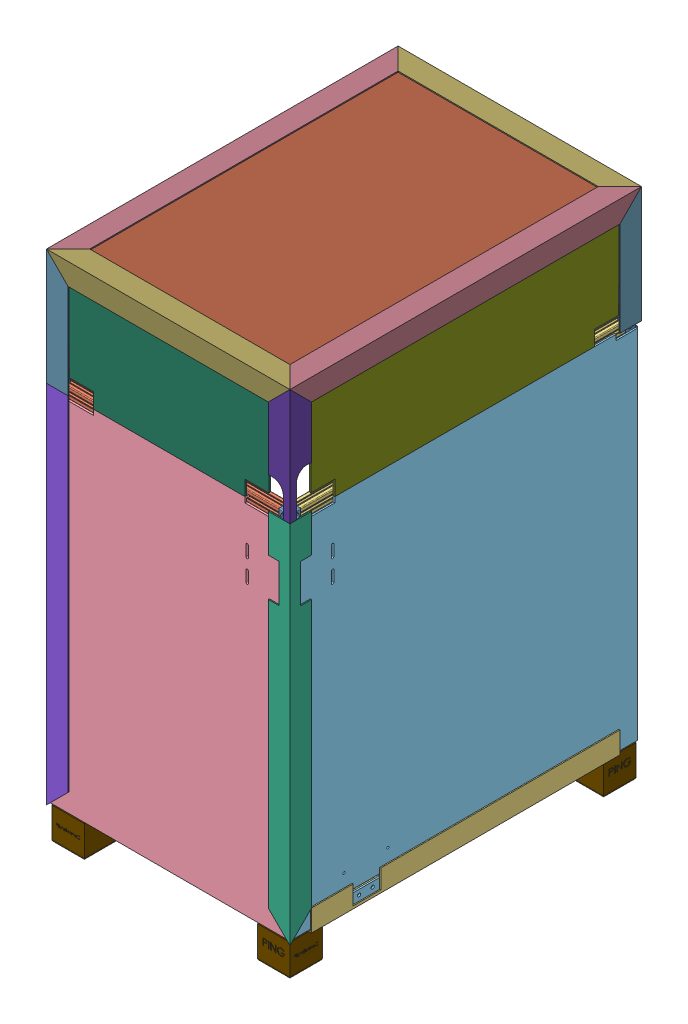
SolidWorks assembly carcasse, configuration Défaut. Lengths in mm.
Overall size (450 950 650).
53 component instances, 24 part files, 63 mates.
Components (placement in the parent):
- cadre-1: cadre [Défaut] at (-215.194 -19.8636 -400) size (440 20 640)
  - Blocks-1: Blocks [Défaut] at (-153.6103 82.5412 1245.1575) x (0 1 0) z (0 0 1) size (20 20 20)
  - Blocks-3: Blocks [Défaut] at (-153.6103 62.5412 625.1575) x (0 0 -1) z (0 1 0) size (20 20 20)
  - Blocks-4: Blocks [Défaut] at (246.3897 82.5412 645.1575) x (0 1 0) z (0 0 -1) size (20 20 20)
  - Blocks-5: Blocks [Défaut] at (246.3897 62.5412 1265.1575) x (0 0 1) z (0 1 0) size (20 20 20)
  - prof_20x20x400mm-1: prof_20x20x400mm [End Finishing_Non-Machined End Finish Options_Type_Single_] at (246.3897 72.5412 635.1575) x (0 0 1) z (-1 0 0) size (20 20 400)
  - prof_20x20x400mm-2: prof_20x20x400mm [End Finishing_Non-Machined End Finish Options_Type_Single_] at (246.3897 72.5412 1255.1575) x (0 0 1) z (-1 0 0) size (20 20 400)
  - prof_20x20x600mm-4: prof_20x20x600mm [End Finishing_Non-Machined End Finish Options_Type_Single_] at (256.3897 72.5412 645.1575) size (20 20 600)
  - prof_20x20x600mm-5: prof_20x20x600mm [End Finishing_Non-Machined End Finish Options_Type_Single_] at (-163.6103 72.5412 645.1575) size (20 20 600)
- prof_20x20x640mm-1: prof_20x20x640mm [End Finishing_Non-Machined End Finish Options_Type_Single_] at (41.1957 42.6776 235.1575) x (1 0 0) z (0 -1 0) size (20 20 640)
- prof_20x20x640mm-2: prof_20x20x640mm [End Finishing_Non-Machined End Finish Options_Type_Single_] at (41.1957 42.6776 855.1575) x (1 0 0) z (0 -1 0) size (20 20 640)
- prof_20x20x640mm-3: prof_20x20x640mm [End Finishing_Non-Machined End Finish Options_Type_Single_] at (-378.8043 42.6776 855.1575) x (1 0 0) z (0 -1 0) size (20 20 640)
- prof_20x20x640mm-4: prof_20x20x640mm [End Finishing_Non-Machined End Finish Options_Type_Single_] at (-378.8043 42.6776 235.1575) x (1 0 0) z (0 -1 0) size (20 20 640)
- cadre-2: cadre [Défaut] at (-122.4146 -534.7812 -400) x (-1 0 0) z (0 0 1) size (440 20 640)
  - Blocks-1: Blocks [Défaut] at (-153.6103 82.5412 1245.1575) x (0 1 0) z (0 0 1) size (20 20 20)
  - Blocks-3: Blocks [Défaut] at (-153.6103 62.5412 625.1575) x (0 0 -1) z (0 1 0) size (20 20 20)
  - Blocks-4: Blocks [Défaut] at (246.3897 82.5412 645.1575) x (0 1 0) z (0 0 -1) size (20 20 20)
  - Blocks-5: Blocks [Défaut] at (246.3897 62.5412 1265.1575) x (0 0 1) z (0 1 0) size (20 20 20)
  - prof_20x20x400mm-1: prof_20x20x400mm [End Finishing_Non-Machined End Finish Options_Type_Single_] at (246.3897 72.5412 635.1575) x (0 0 1) z (-1 0 0) size (20 20 400)
  - prof_20x20x400mm-2: prof_20x20x400mm [End Finishing_Non-Machined End Finish Options_Type_Single_] at (246.3897 72.5412 1255.1575) x (0 0 1) z (-1 0 0) size (20 20 400)
  - prof_20x20x600mm-4: prof_20x20x600mm [End Finishing_Non-Machined End Finish Options_Type_Single_] at (256.3897 72.5412 645.1575) size (20 20 600)
  - prof_20x20x600mm-5: prof_20x20x600mm [End Finishing_Non-Machined End Finish Options_Type_Single_] at (-163.6103 72.5412 645.1575) size (20 20 600)
- plaque_acrylique_680x670-2: plaque_acrylique_680x670 [Défaut] at (51.1957 -282.3224 525.1575) x (0 0 -1) z (1 0 0) size (640 670 3)
- plaque_acrylique_380x670_G-1: plaque_acrylique_380x670_G [Défaut] at (-138.8043 -282.3224 222.1575) size (440 670 3)
- plaque_acrylique_680x670_porte-1: plaque_acrylique_680x670_porte [Défaut] at (-391.8043 -282.3224 525.1575) x (0 0 -1) z (1 0 0) size (640 670 3)
- eclisse_40x40x670_bisote_x1-1: eclisse_40x40x670_bisote_x1 [Défaut] at (-373.8043 -622.3224 240.2711) size (40 675 40)
- eclisse_40x40x670_bisote_x1-2: eclisse_40x40x670_bisote_x1 [Défaut] at (-373.6907 -622.3224 850.1575) x (0 0 -1) z (1 0 0) size (40 675 40)
- eclisse_40x40x670_bisote_x1-4: eclisse_40x40x670_bisote_x1 [Défaut] at (36.0821 -622.3224 240.1575) x (0 0 1) z (-1 0 0) size (40 675 40) (hidden)
- couvercle-1: couvercle [Défaut] at (191.3923 156.5575 835.9918) size (450 215 650)
  - plaque_acrylique_680x210-2: plaque_acrylique_680x210 [Défaut] at (-583.1966 1.1201 -270.8343) x (0 0 -1) z (1 0 0) size (640 210 3)
  - plaque_acrylique_380x210-2: plaque_acrylique_380x210 [Défaut] at (-330.1966 1.1201 -613.8343) size (440 210 3)
  - plaque_acrylique_380x680-1: plaque_acrylique_380x680 [Défaut] at (-330.1966 106.1201 -270.8343) x (1 0 0) z (0 1 0) size (440 640 3)
  - eclisse_40x40x404_bisote_x2-1: eclisse_40x40x404_bisote_x2 [Défaut] at (-135.1966 91.0065 -595.8343) x (0 0 1) z (0 -1 0) size (40 450 40)
  - eclisse_40x40x704_bisote_x2-1: eclisse_40x40x704_bisote_x2 [Défaut] at (-155.3102 91.1201 -615.8343) x (0 -1 0) z (-1 0 0) size (40 650 40)
  - eclisse_40x40x404_bisote_x2-2: eclisse_40x40x404_bisote_x2 [Défaut] at (-585.1966 91.0065 14.1657) x (0 0 -1) z (0 -1 0) size (40 450 40)
  - eclisse_40x40x704_bisote_x2-2: eclisse_40x40x704_bisote_x2 [Défaut] at (-565.1966 91.0065 -615.8343) x (1 0 0) z (0 -1 0) size (40 650 40)
  - eclisse_40x40x222_bisote_x1-1: eclisse_40x40x222_bisote_x1 [Défaut] at (-565.083 111.1201 -595.8343) x (0 0 1) z (1 0 0) size (40 215 40)
  - eclisse_40x40x222_bisote_x1-2: eclisse_40x40x222_bisote_x1 [Défaut] at (-155.1966 111.1201 -595.7207) x (-1 0 0) z (0 0 1) size (40 215 40)
  - eclisse_40x40x222_bisote_x1-4: eclisse_40x40x222_bisote_x1 [Défaut] at (-565.1966 111.1201 14.052) x (1 0 0) z (0 0 -1) size (40 215 40)
  - plaque_acrylique_380x210_Moteur-1: plaque_acrylique_380x210_Moteur [Défaut] at (-330.1966 1.1201 29.1657) size (440 210 3)
  - plaque_acrylique_680x210_moteur-1: plaque_acrylique_680x210_moteur [Défaut] at (-140.1966 1.1201 -270.8343) x (0 0 -1) z (1 0 0) size (640 210 3)
  - eclisse_40x40x222_bisote_x1_Moteur-1: eclisse_40x40x222_bisote_x1_Moteur [Défaut] at (-155.3102 111.1201 14.1657) x (0 0 -1) z (-1 0 0) size (40 215 40)
- Pied-1: Pied [Défaut] at (-8.8043 -622.3224 285.1575) x (-1 0 0) z (0 -1 0) size (60 60 60)
- Pied-2: Pied [Défaut] at (-8.8043 -622.3224 805.1575) x (0 0 -1) z (0 -1 0) size (60 60 60)
- Pied-3: Pied [Défaut] at (-328.8043 -622.3224 805.1575) x (1 0 0) z (0 -1 0) size (60 60 60)
- Pied-4: Pied [Défaut] at (-328.8043 -622.3224 285.1575) x (0 0 1) z (0 -1 0) size (60 60 60)
- eclisse_bas_40x40x704-2: eclisse_bas_40x40x704 [Défaut] at (-373.8043 -602.2087 830.1575) x (1 0 0) z (0 1 0) size (40 570 40) (hidden)
- eclisse_bas_40x40x404-1: eclisse_bas_40x40x404 [Défaut] at (-353.8043 -602.2087 240.1575) x (0 0 1) z (0 1 0) size (40 370 40) (hidden)
- eclisse_bas_40x40x404-2: eclisse_bas_40x40x404 [Défaut] at (16.1957 -602.2087 850.1575) x (0 0 -1) z (0 1 0) size (40 370 40) (hidden)
- eclisse_bas_support_Z_40x40x704-1: eclisse_bas_support_Z_40x40x704 [Défaut] at (36.0821 -602.3224 830.1575) x (0 1 0) z (-1 0 0) size (40 570 40) (hidden)
- plaque_acrylique_380x670_D-2: plaque_acrylique_380x670_D [Défaut] at (-198.8043 -282.3224 848.1575) x (-1 0 0) z (0 0 -1) size (440 670 23) (hidden)
- plaque_acrylique_bas_380x680-1: plaque_acrylique_bas_380x680 [Défaut] at (-138.8043 -620.3224 565.1575) x (1 0 0) z (0 1 0) size (440 640 3)
- eclisse_40x40x670_bisote_x1-Moteur-1: eclisse_40x40x670_bisote_x1-Moteur [Défaut] at (36.1957 -622.3224 850.0438) x (-1 0 0) z (0 0 -1) size (40 675 40) (hidden)
Mates (geometry in assembly coordinates):
- Coïncidente66: coincident anti-aligned: plane of plaque_acrylique_680x670_porte-1 through (-391.8043 -282.3224 525.1575) normal (-1 0 0); plane of eclisse_40x40x670_bisote_x1-1 through (-391.8043 52.6776 222.1575) normal (1 0 0)
- Coïncidente67: coincident aligned: plane of plaque_acrylique_680x670_porte-1 through (-388.8043 52.6776 865.1575) normal (0 1 0); plane of eclisse_40x40x670_bisote_x1-1 through (-373.8043 52.6776 240.2711) normal (0 1 0)
- Coïncidente68: coincident anti-aligned: plane of plaque_acrylique_680x670-2 through (54.1957 -282.3224 525.1575) normal (1 0 0); plane of eclisse_40x40x670_bisote_x1-4 through (54.1957 52.6776 222.1575) normal (-1 0 0)
- Coïncidente72: coincident anti-aligned: plane of plaque_acrylique_680x670_porte-1 through (-391.8043 -282.3224 525.1575) normal (-1 0 0); plane of eclisse_40x40x670_bisote_x1-2 through (-391.8043 52.6776 868.1575) normal (1 0 0)
- Coïncidente100: coincident: plane of plaque_acrylique_680x670_porte-1 through (-388.8043 52.6776 865.1575) normal (0 1 0); line of eclisse_40x40x670_bisote_x1-2 through (-391.8043 52.6776 868.1575) axis (0 0 -1)
- Coïncidente132: coincident anti-aligned: plane of plaque_acrylique_680x670_porte-1 through (-391.8043 -282.3224 525.1575) normal (-1 0 0); plane of eclisse_bas_40x40x704-2 through (-391.8043 -620.3224 260.1575) normal (1 0 0)
- Coïncidente134: coincident anti-aligned: line of eclisse_40x40x670_bisote_x1-2 through (-393.8043 52.6776 830.1575) axis (0 -1 0); line of eclisse_bas_40x40x704-2 through (-393.8043 -622.3224 830.1575) axis (0 1 0)
- Coïncidente142: coincident anti-aligned: plane of plaque_acrylique_680x670-2 through (54.1957 -282.3224 525.1575) normal (1 0 0); plane of eclisse_bas_support_Z_40x40x704-1 through (54.1957 -620.3224 260.1575) normal (-1 0 0)
- Coïncidente156: coincident anti-aligned: plane of eclisse_bas_40x40x404-2 through (-353.8043 -620.3224 868.1575) normal (0 0 -1); plane of plaque_acrylique_380x670_D-2 through (-198.8043 -282.3224 868.1575) normal (0 0 1)
- Coïncidente157: coincident anti-aligned: plane of eclisse_40x40x670_bisote_x1-2 through (-391.8043 52.6776 868.1575) normal (0 0 -1); plane of plaque_acrylique_380x670_D-2 through (-198.8043 -282.3224 868.1575) normal (0 0 1)
- Coïncidente163: coincident anti-aligned: plane of cadre-1/Blocks-1 through (-388.8043 42.6776 865.1575) normal (0 -1 0); plane of prof_20x20x640mm-3 through (-387.3043 42.6776 863.6575) normal (0 1 0)
- Coïncidente164: coincident aligned: plane of cadre-1/Blocks-1 through (-388.8043 42.6776 865.1575) normal (-1 0 0); plane of prof_20x20x640mm-3 through (-388.8043 -597.3224 858.9075) normal (-1 0 0)
- Coïncidente165: coincident aligned: plane of cadre-1/Blocks-1 through (-368.8043 62.6776 865.1575) normal (0 0 1); plane of prof_20x20x640mm-3 through (-382.5543 -597.3224 865.1575) normal (0 0 1)
- Coïncidente166: coincident anti-aligned: plane of prof_20x20x640mm-3 through (-387.3043 -597.3224 863.6575) normal (0 -1 0); plane of cadre-2/Blocks-5 through (-368.8043 -597.3224 865.1575) normal (0 1 0)
- Coïncidente167: coincident aligned: plane of prof_20x20x640mm-3 through (-382.5543 -597.3224 865.1575) normal (0 0 1); plane of cadre-2/Blocks-5 through (-388.8043 -617.3224 865.1575) normal (0 0 1)
- Coïncidente168: coincident aligned: plane of prof_20x20x640mm-3 through (-388.8043 -597.3224 858.9075) normal (-1 0 0); plane of cadre-2/Blocks-5 through (-388.8043 -617.3224 845.1575) normal (-1 0 0)
- Coïncidente169: coincident anti-aligned: plane of prof_20x20x640mm-2 through (32.6957 -597.3224 863.6575) normal (0 -1 0); plane of cadre-2/Blocks-1 through (51.1957 -597.3224 865.1575) normal (0 1 0)
- Coïncidente170: coincident aligned: plane of prof_20x20x640mm-2 through (37.4457 -597.3224 865.1575) normal (0 0 1); plane of cadre-2/Blocks-1 through (31.1957 -617.3224 865.1575) normal (0 0 1)
- Coïncidente171: coincident aligned: plane of prof_20x20x640mm-2 through (51.1957 -597.3224 858.9075) normal (1 0 0); plane of cadre-2/Blocks-1 through (51.1957 -597.3224 865.1575) normal (1 0 0)
- Coïncidente172: coincident anti-aligned: plane of prof_20x20x640mm-1 through (32.6957 -597.3224 243.6575) normal (0 -1 0); plane of cadre-2/Blocks-3 through (31.1957 -597.3224 225.1575) normal (0 1 0)
- Coïncidente173: coincident aligned: plane of prof_20x20x640mm-1 through (51.1957 -597.3224 238.9075) normal (1 0 0); plane of cadre-2/Blocks-3 through (51.1957 -617.3224 245.1575) normal (1 0 0)
- Coïncidente174: coincident aligned: plane of prof_20x20x640mm-1 through (44.9457 -597.3224 225.1575) normal (0 0 -1); plane of cadre-2/Blocks-3 through (51.1957 -617.3224 225.1575) normal (0 0 -1)
- Coïncidente175: coincident aligned: plane of cadre-1/Blocks-3 through (-388.8043 62.6776 245.1575) normal (-1 0 0); plane of prof_20x20x640mm-4 through (-388.8043 -597.3224 231.4075) normal (-1 0 0)
- Coïncidente176: coincident aligned: plane of cadre-1/Blocks-3 through (-388.8043 62.6776 225.1575) normal (0 0 -1); plane of prof_20x20x640mm-4 through (-382.5543 -597.3224 225.1575) normal (0 0 -1)
- Coïncidente177: coincident anti-aligned: plane of cadre-1/Blocks-3 through (-368.8043 42.6776 225.1575) normal (0 -1 0); plane of prof_20x20x640mm-4 through (-387.3043 42.6776 243.6575) normal (0 1 0)
- Coïncidente183: coincident aligned: plane of prof_20x20x640mm-2 through (51.1957 -597.3224 858.9075) normal (1 0 0); plane of plaque_acrylique_380x670_D-2 through (51.1957 52.6776 868.1575) normal (1 0 0)
- Coïncidente186: coincident aligned: plane of cadre-1/prof_20x20x400mm-2 through (-368.8043 56.4276 865.1575) normal (0 0 1); plane of plaque_acrylique_680x670-2 through (54.1957 52.6776 865.1575) normal (0 0 1)
- Coïncidente187: coincident aligned: plane of cadre-1/prof_20x20x400mm-1 through (-368.8043 48.9276 225.1575) normal (0 0 -1); plane of plaque_acrylique_680x670_porte-1 through (-388.8043 52.6776 225.1575) normal (0 0 -1)
- Coïncidente191: coincident anti-aligned: plane of cadre-2/prof_20x20x400mm-1 through (31.1957 -617.3224 238.9075) normal (0 -1 0); plane of plaque_acrylique_bas_380x680-1 through (-138.8043 -617.3224 565.1575) normal (0 1 0)
- Coïncidente192: coincident aligned: plane of cadre-2/prof_20x20x400mm-2 through (31.1957 -611.0724 865.1575) normal (0 0 1); plane of plaque_acrylique_bas_380x680-1 through (-388.8043 -617.3224 865.1575) normal (0 0 1)
- Coïncidente204: coincident anti-aligned: plane of prof_20x20x640mm-1 through (44.9457 -597.3224 225.1575) normal (0 0 -1); plane of plaque_acrylique_380x670_G-1 through (-138.8043 -282.3224 225.1575) normal (0 0 1)
- Coïncidente205: coincident aligned: plane of cadre-2/prof_20x20x400mm-1 through (31.1957 -617.3224 231.4075) normal (0 -1 0); plane of plaque_acrylique_380x670_G-1 through (-388.8043 -617.3224 225.1575) normal (0 -1 0)
- Coïncidente206: coincident aligned: plane of prof_20x20x640mm-1 through (51.1957 -597.3224 231.4075) normal (1 0 0); plane of plaque_acrylique_380x670_G-1 through (51.1957 52.6776 225.1575) normal (1 0 0)
- Coïncidente207: coincident anti-aligned: plane of prof_20x20x640mm-4 through (-388.8043 -597.3224 231.4075) normal (-1 0 0); plane of plaque_acrylique_680x670_porte-1 through (-388.8043 -282.3224 525.1575) normal (1 0 0)
- Coïncidente208: coincident anti-aligned: plane of plaque_acrylique_380x670_G-1 through (-138.8043 -282.3224 222.1575) normal (0 0 -1); plane of eclisse_40x40x670_bisote_x1-1 through (-391.8043 52.6776 222.1575) normal (0 0 1)
- Coïncidente210: coincident anti-aligned: plane of plaque_acrylique_380x670_G-1 through (-138.8043 -282.3224 222.1575) normal (0 0 -1); plane of eclisse_40x40x670_bisote_x1-4 through (54.1957 52.6776 222.1575) normal (0 0 1)
- Coïncidente218: coincident: plane of cadre-2/prof_20x20x400mm-2 through (31.1957 -617.3224 858.9075) normal (0 -1 0); line of plaque_acrylique_380x670_D-2 through (51.1957 -617.3224 868.1575) axis (-1 0 0)
- Coïncidente223: coincident anti-aligned: plane of eclisse_bas_support_Z_40x40x704-1 through (54.1957 -620.3224 260.1575) normal (0 1 0); plane of plaque_acrylique_bas_380x680-1 through (-138.8043 -620.3224 565.1575) normal (0 -1 0)
- Coïncidente224: coincident anti-aligned: plane of eclisse_bas_40x40x704-2 through (-391.8043 -620.3224 260.1575) normal (0 1 0); plane of plaque_acrylique_bas_380x680-1 through (-138.8043 -620.3224 565.1575) normal (0 -1 0)
- Coïncidente225: coincident anti-aligned: plane of plaque_acrylique_380x670_G-1 through (-138.8043 -282.3224 222.1575) normal (0 0 -1); plane of eclisse_bas_40x40x404-1 through (16.1957 -620.3224 222.1575) normal (0 0 1)
- Coïncidente226: coincident anti-aligned: plane of eclisse_bas_40x40x404-1 through (16.1957 -620.3224 222.1575) normal (0 1 0); plane of plaque_acrylique_bas_380x680-1 through (-138.8043 -620.3224 565.1575) normal (0 -1 0)
- Coïncidente232: coincident aligned: plane of plaque_acrylique_380x670_G-1 through (-138.8043 -282.3224 222.1575) normal (0 0 -1); plane of couvercle-1/plaque_acrylique_380x210-2 through (-138.8043 157.6776 222.1575) normal (0 0 -1)
- Coïncidente233: coincident aligned: plane of couvercle-1/plaque_acrylique_380x210_Moteur-1 through (-138.8043 157.6776 868.1575) normal (0 0 1); plane of plaque_acrylique_380x670_D-2 through (-198.8043 -282.3224 868.1575) normal (0 0 1)
- Coïncidente234: coincident anti-aligned: line of plaque_acrylique_680x670-2 through (54.1957 52.6776 225.1575) axis (0 0 1); line of couvercle-1/plaque_acrylique_680x210_moteur-1 through (54.1957 52.6776 825.1575) axis (0 0 -1)
- Coïncidente235: coincident aligned: plane of plaque_acrylique_680x670-2 through (54.1957 -282.3224 525.1575) normal (1 0 0); plane of couvercle-1/plaque_acrylique_680x210_moteur-1 through (54.1957 157.6776 565.1575) normal (1 0 0)
- Coïncidente236: coincident anti-aligned: plane of plaque_acrylique_680x670-2 through (54.1957 -282.3224 525.1575) normal (1 0 0); plane of eclisse_40x40x670_bisote_x1-Moteur-1 through (54.1957 52.6776 868.1575) normal (-1 0 0)
- Coïncidente237: coincident anti-aligned: plane of plaque_acrylique_380x670_D-2 through (-198.8043 -282.3224 868.1575) normal (0 0 1); plane of eclisse_40x40x670_bisote_x1-Moteur-1 through (54.1957 52.6776 868.1575) normal (0 0 -1)
- Coïncidente239: coincident anti-aligned: plane of plaque_acrylique_680x670_porte-1 through (-388.8043 -282.3224 525.1575) normal (1 0 0); plane of plaque_acrylique_bas_380x680-1 through (-388.8043 -617.3224 225.1575) normal (-1 0 0)
- Coïncidente240: coincident anti-aligned: plane of cadre-2/prof_20x20x600mm-5 through (51.1957 -611.0724 845.1575) normal (1 0 0); plane of plaque_acrylique_680x670-2 through (51.1957 -282.3224 525.1575) normal (-1 0 0)
- Coïncidente241: coincident aligned: plane of cadre-2/prof_20x20x600mm-5 through (44.9457 -617.3224 845.1575) normal (0 -1 0); plane of plaque_acrylique_680x670-2 through (54.1957 -617.3224 865.1575) normal (0 -1 0)
- Coïncidente242: coincident aligned: plane of cadre-2/prof_20x20x600mm-4 through (-382.5543 -617.3224 845.1575) normal (0 -1 0); plane of plaque_acrylique_680x670_porte-1 through (-388.8043 -617.3224 865.1575) normal (0 -1 0)
- Coïncidente243: coincident anti-aligned: plane of eclisse_bas_40x40x404-2 through (-353.8043 -620.3224 868.1575) normal (0 1 0); plane of plaque_acrylique_bas_380x680-1 through (-138.8043 -620.3224 565.1575) normal (0 -1 0)
- Coïncidente244: coincident anti-aligned: plane of Pied-2 through (-8.8043 -622.3224 805.1575) normal (0 1 0); plane of eclisse_bas_40x40x404-2 through (-353.8043 -622.3224 870.1575) normal (0 -1 0)
- Coïncidente245: coincident anti-aligned: plane of Pied-4 through (-328.8043 -622.3224 285.1575) normal (0 1 0); plane of eclisse_bas_40x40x704-2 through (-393.8043 -622.3224 260.1575) normal (0 -1 0)
- Coïncidente246: coincident anti-aligned: plane of Pied-1 through (-8.8043 -622.3224 285.1575) normal (0 1 0); plane of eclisse_bas_40x40x404-1 through (16.1957 -622.3224 220.1575) normal (0 -1 0)
- Coïncidente247: coincident aligned: plane of cadre-2/prof_20x20x600mm-4 through (-388.8043 -603.5724 845.1575) normal (-1 0 0); plane of Pied-3 through (-388.8043 -682.3224 805.1575) normal (-1 0 0)
- Coïncidente249: coincident aligned: plane of cadre-2/prof_20x20x400mm-2 through (31.1957 -611.0724 865.1575) normal (0 0 1); plane of Pied-3 through (-328.8043 -682.3224 865.1575) normal (0 0 1)
- Coïncidente250: coincident aligned: plane of cadre-2/prof_20x20x600mm-5 through (51.1957 -603.5724 845.1575) normal (1 0 0); plane of Pied-2 through (51.1957 -682.3224 805.1575) normal (1 0 0)
- Coïncidente251: coincident aligned: plane of cadre-2/prof_20x20x400mm-2 through (31.1957 -603.5724 865.1575) normal (0 0 1); plane of Pied-2 through (-8.8043 -682.3224 865.1575) normal (0 0 1)
- Coïncidente252: coincident aligned: plane of cadre-2/prof_20x20x600mm-5 through (51.1957 -611.0724 845.1575) normal (1 0 0); plane of Pied-1 through (51.1957 -682.3224 285.1575) normal (1 0 0)
- Coïncidente253: coincident aligned: plane of cadre-2/prof_20x20x400mm-1 through (31.1957 -611.0724 225.1575) normal (0 0 -1); plane of Pied-1 through (-8.8043 -682.3224 225.1575) normal (0 0 -1)
- Coïncidente254: coincident aligned: plane of cadre-2/prof_20x20x600mm-4 through (-388.8043 -611.0724 845.1575) normal (-1 0 0); plane of Pied-4 through (-388.8043 -682.3224 285.1575) normal (-1 0 0)
- Coïncidente255: coincident aligned: plane of cadre-2/prof_20x20x400mm-1 through (31.1957 -611.0724 225.1575) normal (0 0 -1); plane of Pied-4 through (-328.8043 -682.3224 225.1575) normal (0 0 -1)
